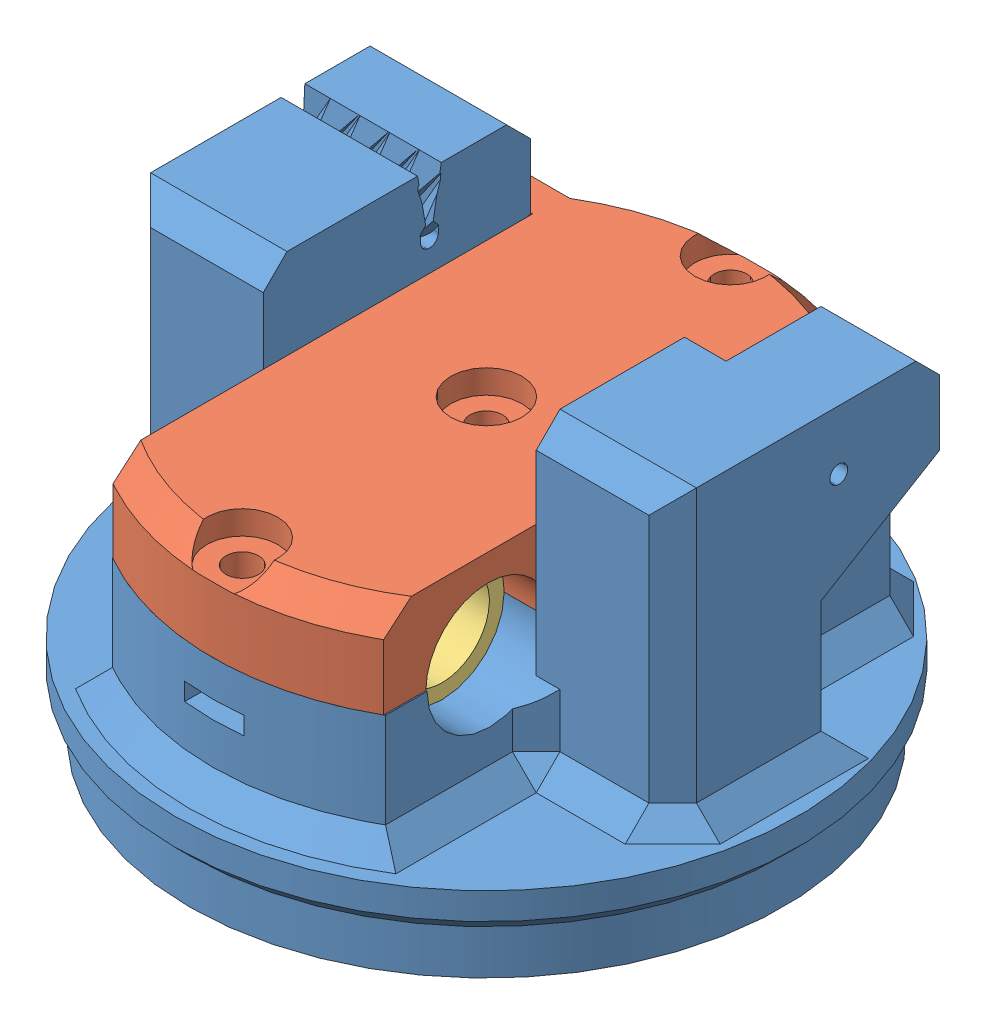
SolidWorks assembly new_striker_assembly, configuration Default. Lengths in mm.
Overall size (105 64.5 105).
5 component instances, 3 part files, 9 mates.
Components (placement in the parent):
- new_striker-1: new_striker [Default] at (-38.6 -27.3858 26.9151) size (105 64.5 105)
- new_striker_bearing_holder-1: new_striker_bearing_holder [Default] at (-38.6 -7.3858 26.9151) x (-1 0 0) z (0 1 0) size (63.6 92.28 15)
- bearing-1: bearing [Default] at (-53.6 -7.3858 49.4151) x (0 0 -1) z (1 0 0) size (24 24 30)
- bearing-2: bearing [Default] at (-68.6 -7.3858 4.4151) x (0 0 -1) z (1 0 0) size (24 24 30)
- bearing-3: bearing [Default] at (-38.6 -7.3858 4.4151) x (0 -0.116572 -0.993182) z (1 0 0) size (24 24 30)
Mates (geometry in assembly coordinates):
- Coincident3: coincident anti-aligned: plane of new_striker-1 through (-38.6 -7.3858 26.9151) normal (0 1 0); plane of new_striker_bearing_holder-1 through (-38.6 -7.3858 26.9151) normal (0 -1 0)
- Concentric2: concentric aligned: cylinder of new_striker-1 through (-38.6 39.6886 26.9151) axis (0 -1 0) radius 46.1411; cylinder of new_striker_bearing_holder-1 through (-38.6 7.6142 26.9151) axis (0 -1 0) radius 46.14
- Parallel1: parallel aligned: plane of new_striker-1 through (-6.6 -7.3858 -13.0849) normal (0 0 -1); plane of new_striker_bearing_holder-1 through (-15.6 7.6142 -13.0837) normal (0 0 -1)
- Concentric3: concentric anti-aligned: cylinder of new_striker-1 through (-70.6 -7.3858 49.4151) axis (1 0 0) radius 12.1; cylinder of bearing-1 through (-23.6 -7.3858 49.4151) axis (-1 0 0) radius 8
- Coincident4: coincident anti-aligned: plane of new_striker-1 through (-23.6 -7.3858 49.4151) normal (-1 0 0); plane of bearing-1 through (-23.6 -7.3858 49.4151) normal (1 0 0)
- Concentric4: concentric aligned: cylinder of bearing-2 through (-38.6 -7.3858 4.4151) axis (-1 0 0) radius 12; cylinder of bearing-3 through (-8.6 -7.3858 4.4151) axis (-1 0 0) radius 12
- Concentric5: concentric anti-aligned: cylinder of new_striker-1 through (-70.6 -7.3858 4.4151) axis (1 0 0) radius 12.1; cylinder of bearing-2 through (-38.6 -7.3858 4.4151) axis (-1 0 0) radius 12
- Coincident5: coincident anti-aligned: plane of new_striker-1 through (-68.6 -7.3858 4.4151) normal (1 0 0); plane of bearing-2 through (-68.6 -7.3858 4.4151) normal (-1 0 0)
- Coincident6: coincident anti-aligned: plane of new_striker-1 through (-8.6 -7.3858 4.4151) normal (-1 0 0); plane of bearing-3 through (-8.6 -7.3858 4.4151) normal (1 0 0)
